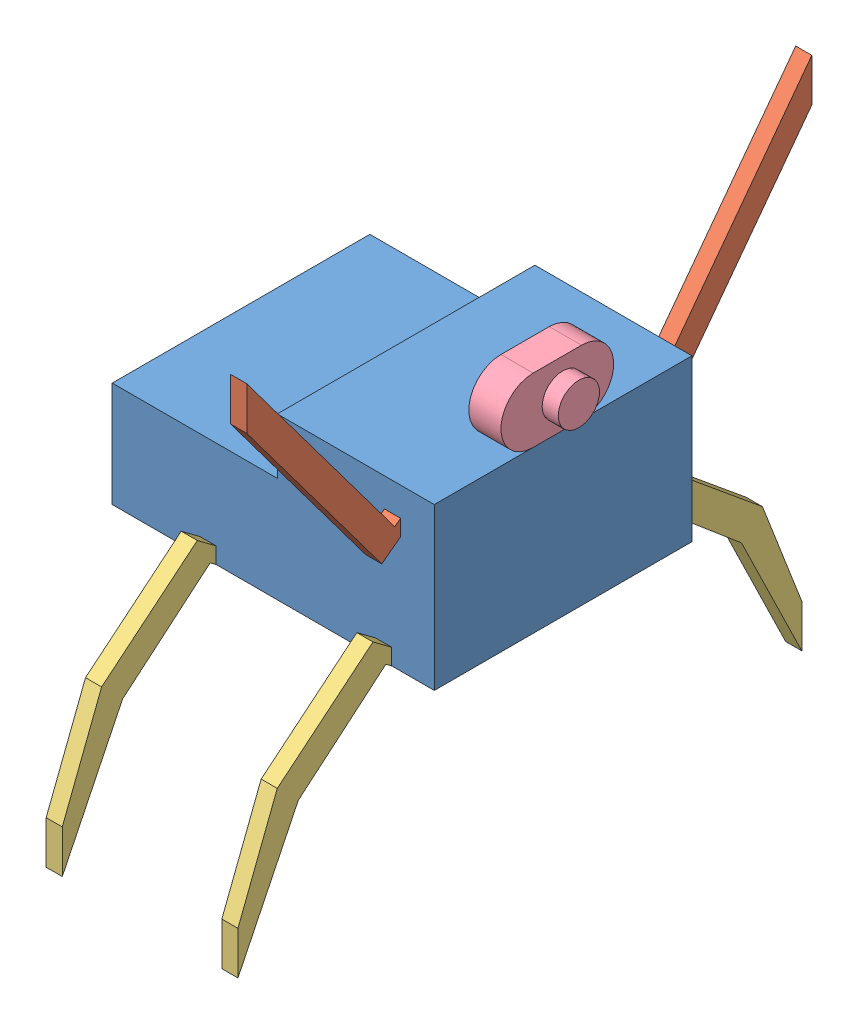
SolidWorks assembly 4 robot, configuration Predeterminado. Lengths in mm.
Overall size (105 161.72 175.51).
8 component instances, 4 part files, 12 mates.
Components (placement in the parent):
- pieza 5-1: pieza 5 [Predeterminado] at (54.7453 -44.2571 100) size (100 50 80)
- pieza 6-1: pieza 6 [Predeterminado] at (31.1903 44.1877 179.3061) x (0 0 -1) z (1 0 0) size (47.76 69.42 5)
- pieza 6-2: pieza 6 [Predeterminado] at (36.1393 44.7223 100.6939) x (0 0 1) z (-1 0 0) size (47.76 69.42 5)
- pieza 7-1: pieza 7 [Predeterminado] at (33.4532 -40.2004 179.3061) x (0 0 -1) z (-1 0 0) size (47.76 69.42 5)
- pieza 7-2: pieza 7 [Predeterminado] at (-21.0937 -40.2004 179.3061) x (0 0 -1) z (-1 0 0) size (47.76 69.42 5)
- pieza 7-3: pieza 7 [Predeterminado] at (28.0189 -40.2004 100.6939) x (0 0 1) z (1 0 0) size (47.76 69.42 5)
- pieza 7-4: pieza 7 [Predeterminado] at (-26.3206 -40.2004 100.6939) x (0 0 1) z (1 0 0) size (47.76 69.42 5)
- pieza 8-1: pieza 8 [Predeterminado] at (36.6642 43.9562 93.9269) x (0 0 -1) z (1 0 0) size (35 20 15)
Mates (geometry in assembly coordinates):
- Coincidente1: coincident anti-aligned: plane of pieza 5-1 through (54.7453 -44.2571 180) normal (0 0 1); plane of pieza 6-1 through (36.1903 22.5381 180) normal (0 0 -1)
- Coincidente2: coincident anti-aligned: plane of pieza 5-1 through (54.7453 -44.2571 100) normal (0 0 -1); plane of pieza 6-2 through (31.1393 23.0727 100) normal (0 0 1)
- Coincidente5: coincident anti-aligned: plane of pieza 5-1 through (54.7453 -44.2571 180) normal (0 0 1); plane of pieza 7-1 through (28.4532 -18.5508 180) normal (0 0 -1)
- Coincidente7: coincident aligned: line of pieza 5-1 through (-53.3358 -18.5508 180) axis (1 0 0); line of pieza 7-1 through (28.4532 -18.5508 180) axis (1 0 0)
- Coincidente8: coincident anti-aligned: plane of pieza 5-1 through (54.7453 -44.2571 180) normal (0 0 1); plane of pieza 7-2 through (-26.0937 -18.5508 180) normal (0 0 -1)
- Coincidente9: coincident aligned: line of pieza 5-1 through (-53.3358 -18.5508 180) axis (1 0 0); line of pieza 7-2 through (-26.0937 -18.5508 180) axis (1 0 0)
- Coincidente10: coincident anti-aligned: plane of pieza 5-1 through (54.7453 -44.2571 100) normal (0 0 -1); plane of pieza 7-3 through (33.0189 -18.5508 100) normal (0 0 1)
- Coincidente12: coincident anti-aligned: line of pieza 5-1 through (-53.3358 -18.5508 100) axis (1 0 0); line of pieza 7-3 through (33.0189 -18.5508 100) axis (-1 0 0)
- Coincidente13: coincident anti-aligned: plane of pieza 5-1 through (54.7453 -44.2571 100) normal (0 0 -1); plane of pieza 7-4 through (-21.3206 -18.5508 100) normal (0 0 1)
- Coincidente14: coincident anti-aligned: line of pieza 5-1 through (-53.3358 -18.5508 100) axis (1 0 0); line of pieza 7-4 through (-21.3206 -18.5508 100) axis (-1 0 0)
- Coincidente15: coincident anti-aligned: plane of pieza 5-1 through (-53.3358 31.4492 180) normal (0 1 0); plane of pieza 8-1 through (46.6642 31.4492 149.2967) normal (0 -1 0)
- Coincidente19: coincident aligned: line of pieza 5-1 through (46.6642 31.4492 180) axis (0 0 -1); line of pieza 8-1 through (46.6642 31.4492 149.2967) axis (0 0 -1)
